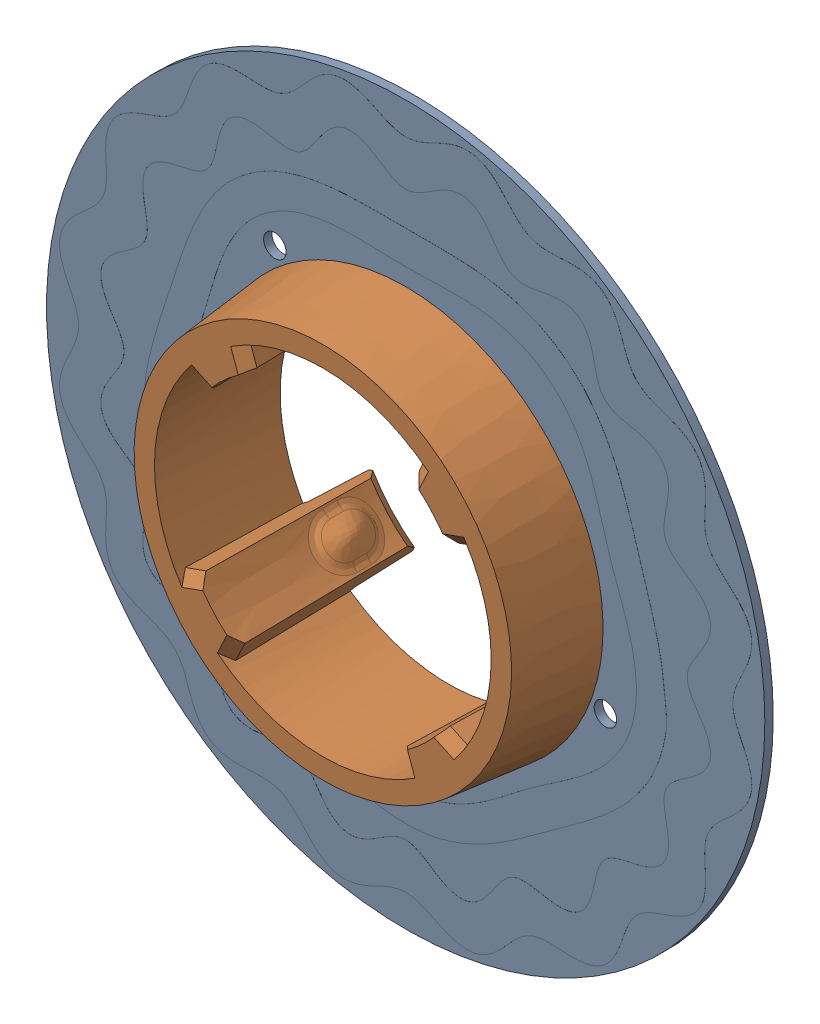
SolidWorks assembly CUI_DEVICES_Overmold_Rev_A, configuration Default. Lengths in mm.
Overall size (25.6 25.6 6.65).
2 component instances, 2 part files, 0 mates.
Components (placement in the parent):
- CUI_DEVICES_Rotor_16f_5c_Rev_D-1: CUI_DEVICES_Rotor_16f_5c_Rev_D [Default] at (-4.5895 18.9245 -10.5857) size (25.6 25.6 0.31)
- CUI_DEVICES_AMT-Overmold_Hub-REV_A-1: CUI_DEVICES_AMT-Overmold_Hub-REV_A [Default] at (-4.5895 18.9245 -10.5807) x (-0.941518 -0.336962 0) z (0 0 1) size (14.07 14.07 6.65)
